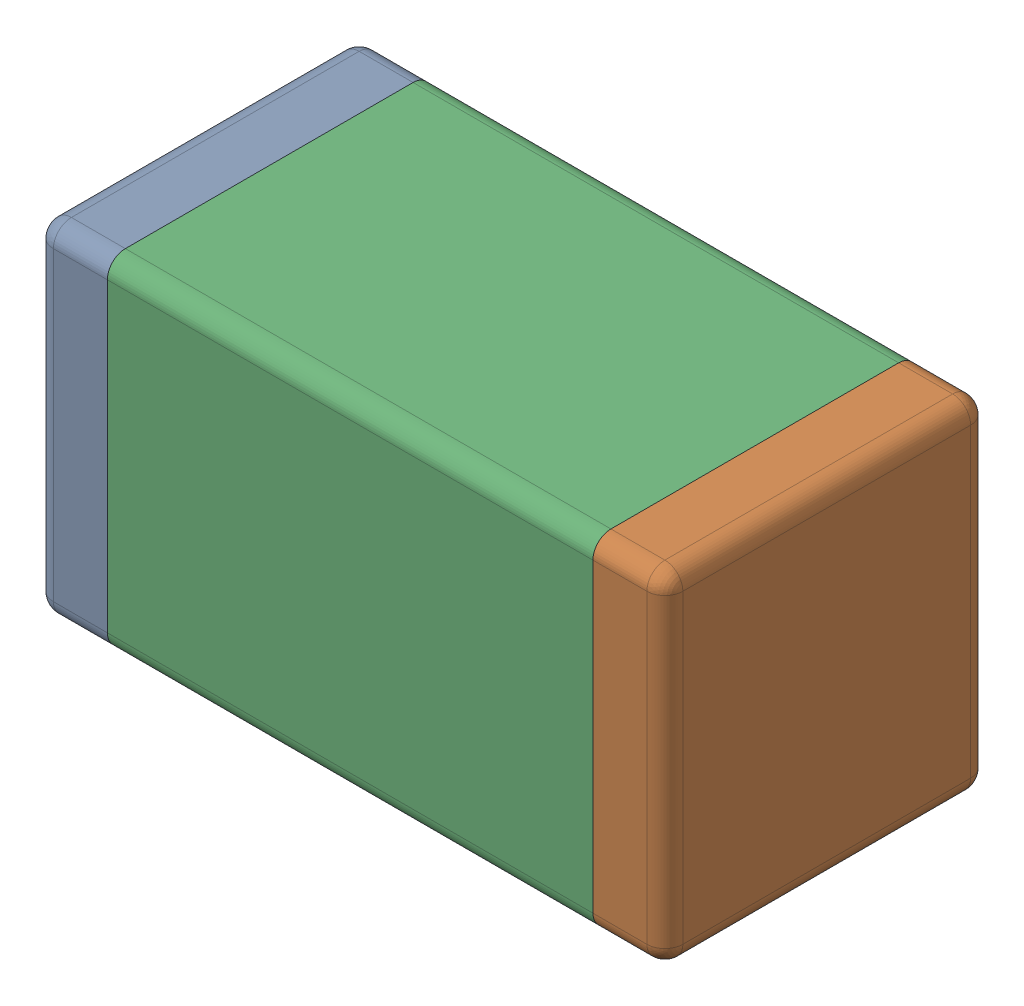
SolidWorks assembly 6033537424, configuration Default. Lengths in mm.
Overall size (1.75 0.95 0.9).
5 component instances, 3 part files, 0 mates.
Components (placement in the parent):
- Terminal_5-1: Terminal_5 [Default] at (-0.875 -0.475 0) size (1.75 0.95 0.9)
  - Open CASCADE STEP translator 6.8 142.1.1-1: Open CASCADE STEP translator 6.8 142.1.1 [Default] at origin size (0.2 0.95 0.9)
  - Open CASCADE STEP translator 6.8 142.1.2-1: Open CASCADE STEP translator 6.8 142.1.2 [Default] at origin size (0.2 0.95 0.9)
- Mid_Body_2-1: Mid_Body_2 [Default] at (-0.875 -0.475 0) size (1.35 0.95 0.9)
  - Open CASCADE STEP translator 6.8 142.2.1-1: Open CASCADE STEP translator 6.8 142.2.1 [Default] at origin size (1.35 0.95 0.9)
